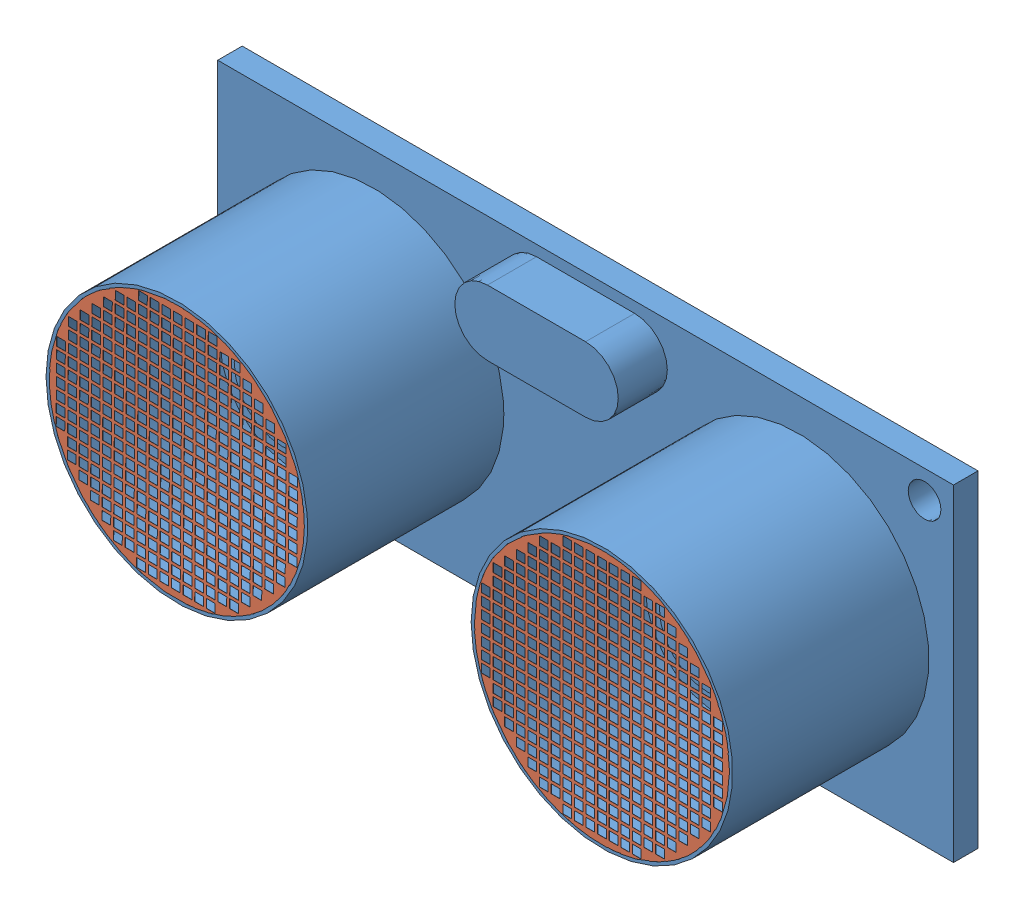
SolidWorks assembly HCSR04FINAL, configuration Predeterminado. Lengths in mm.
Overall size (45 25.5 16.5).
3 component instances, 2 part files, 4 mates.
Components (placement in the parent):
- HC-SR04-1: HC-SR04 [Predeterminado] at (-3.0919 -1.665 39.75) size (45 25.5 16.5)
- RED-1: RED [Predeterminado] at (-16.0919 1.685 53.24) x (0.999967 -0.008112 0) z (0 0 1) size (15.6 15.6 0.01)
- RED-2: RED [Predeterminado] at (9.9081 1.685 53.24) size (15.6 15.6 0.01)
Mates (geometry in assembly coordinates):
- Concéntrica1: concentric aligned: cylinder of HC-SR04-1 through (-16.0919 1.685 53.25) axis (0 0 -1) radius 7.8; cylinder of RED-1 through (-16.0919 1.685 53.25) axis (0 0 -1) radius 7.8
- Coincidente2: coincident aligned: circle of HC-SR04-1; circle of RED-1
- Concéntrica2: concentric aligned: cylinder of HC-SR04-1 through (9.9081 1.685 53.25) axis (0 0 -1) radius 7.8; cylinder of RED-2 through (9.9081 1.685 53.25) axis (0 0 -1) radius 7.8
- Coincidente4: coincident aligned: circle of HC-SR04-1; circle of RED-2
